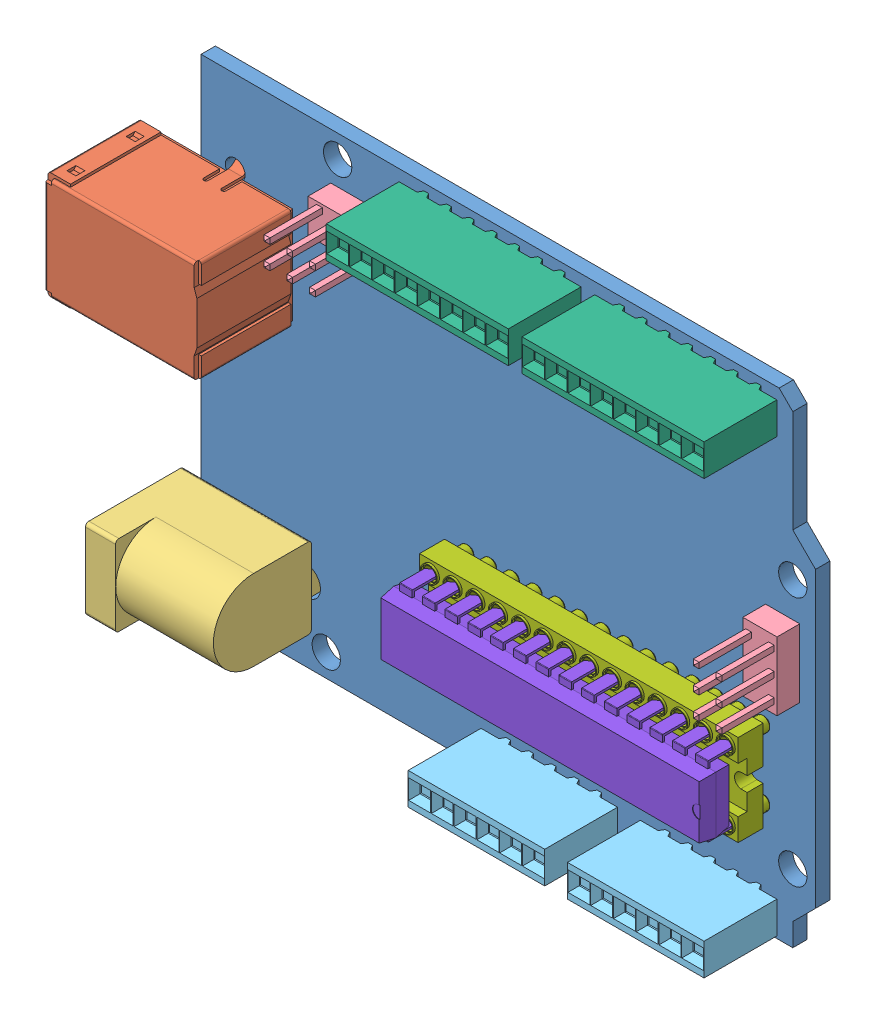
SolidWorks assembly uno-assy, configuration Default. Lengths in mm.
Overall size (75.05 53.34 15.91).
11 component instances, 8 part files, 29 mates.
Components (placement in the parent):
- uno-pcb-1: uno-pcb [Default] at origin size (68.58 53.34 1.6)
- SW3dPS-67068-0000-molex-1: SW3dPS-67068-0000-molex [Default] at (-40.7599 11.4299 0) x (0 -1 0) z (-1 0 0) size (14.9 15.43 17)
- RAPC732-1: RAPC732 [Default] at (-21.9709 -14.1224 0) x (0 -1 0) z (-1 0 0) size (11.28 14.91 15.39)
- 3x2-100-1: 3x2-100 [Default] at (-18.5421 20.828 0) size (7.62 3.81 11.94)
- 3x2-100-2: 3x2-100 [Default] at (29.3502 -1.32 0) x (0 1 0) z (0 0 1) size (7.62 3.81 11.94)
- C-0534237-04-3-1: C-0534237-04-3 [Default] at (22.8599 -24.13 8.636) x (-1 0 0) z (0 0 1) size (15.24 3.56 11.56)
- C-0534237-06-3-1: C-0534237-06-3 [Default] at (20.3199 24.13 8.636) x (-1 0 0) z (0 0 1) size (20.32 3.56 11.56)
- C-0534237-04-3-2: C-0534237-04-3 [Default] at (5.0799 -24.13 8.636) x (-1 0 0) z (0 0 1) size (15.24 3.56 11.56)
- C-0534237-06-3-2: C-0534237-06-3 [Default] at (-1.5241 24.13 8.636) x (-1 0 0) z (0 0 1) size (20.32 3.56 11.56)
- 28pdipskt-1: 28pdipskt [Default] at (24.7649 -10.287 1.4) x (0 -1 0) z (0 0 1) size (10.16 35.56 7.62)
- User Library-28 pin dip-1: User Library-28 pin dip [Default] at (6.9849 -10.287 6.873) x (0 1 0) z (1 0 0) size (7.87 6.22 35.94)
Mates (geometry in assembly coordinates):
- Coincident1: coincident aligned: axis of uno-pcb-1 through (-27.7699 12.6799 -1.6002) axis (0 0 1); axis of SW3dPS-67068-0000-molex-1 through (-27.7699 12.6799 -2.8) axis (0 0 1)
- Coincident2: coincident anti-aligned: plane of uno-pcb-1 through (-34.2899 26.67 0) normal (0 0 1); plane of SW3dPS-67068-0000-molex-1 through (-23.7599 17.4299 0) normal (0 0 -1)
- Parallel1: parallel aligned: plane of uno-pcb-1 through (-34.2899 -26.67 -1.6002) normal (-1 0 0); plane of SW3dPS-67068-0000-molex-1 through (-40.7599 17.4299 11) normal (-1 0 0)
- Concentric1: concentric aligned: circle of uno-pcb-1; circle of RAPC732-1
- Parallel2: parallel aligned: plane of uno-pcb-1 through (-34.2899 -26.67 -1.6002) normal (-1 0 0); plane of RAPC732-1 through (-36.2203 -14.5034 10.5918) normal (-1 0 0)
- Coincident5: coincident anti-aligned: plane of uno-pcb-1 through (-34.2899 26.67 0) normal (0 0 1); plane of RAPC732-1 through (-36.2203 -14.5034 0) normal (0 0 -1)
- Coincident6: coincident aligned: axis of uno-pcb-1 through (-18.5421 18.288 -1.6002) axis (0 0 1); axis of 3x2-100-1 through (-18.5421 18.288 -3.302) axis (0 0 1)
- Coincident7: coincident anti-aligned: plane of uno-pcb-1 through (-34.2899 26.67 0) normal (0 0 1); plane of 3x2-100-1 through (-18.5421 20.828 0) normal (0 0 -1)
- Coincident8: coincident aligned: axis of uno-pcb-1 through (31.8902 -1.32 -1.6002) axis (0 0 1); axis of 3x2-100-2 through (31.8902 -1.32 -3.302) axis (0 0 1)
- Coincident9: coincident anti-aligned: plane of uno-pcb-1 through (-34.2899 26.67 0) normal (0 0 1); plane of 3x2-100-2 through (29.3502 -1.32 0) normal (0 0 -1)
- Parallel3: parallel anti-aligned: plane of uno-pcb-1 through (34.2899 -21.59 -1.6002) normal (1 0 0); plane of 3x2-100-2 through (28.7152 -2.59 2.54) normal (-1 0 0)
- Parallel4: parallel aligned: plane of uno-pcb-1 through (-34.2899 26.67 -1.6002) normal (0 1 0); plane of 3x2-100-1 through (-19.8121 21.463 2.54) normal (0 1 0)
- Coincident12: coincident anti-aligned: axis of uno-pcb-1 through (29.2099 -24.13 -1.6002) axis (0 0 1); axis of C-0534237-04-3-1 through (29.2099 -24.13 -0.846) axis (0 0 -1)
- Parallel5: parallel aligned: plane of uno-pcb-1 through (-34.2899 -26.67 -1.6002) normal (0 -1 0); plane of C-0534237-04-3-1 through (30.4799 -25.908 8.636) normal (0 -1 0)
- Coincident15: coincident anti-aligned: axis of uno-pcb-1 through (11.4299 -24.13 -1.6002) axis (0 0 1); axis of C-0534237-04-3-2 through (11.4299 -24.13 -0.846) axis (0 0 -1)
- Coincident16: coincident anti-aligned: plane of uno-pcb-1 through (-34.2899 26.67 0) normal (0 0 1); plane of C-0534237-04-3-2 through (10.4139 -25.908 0) normal (0 0 -1)
- Coincident17: coincident anti-aligned: plane of uno-pcb-1 through (-34.2899 26.67 0) normal (0 0 1); plane of C-0534237-04-3-1 through (28.1939 -25.908 0) normal (0 0 -1)
- Coincident18: coincident anti-aligned: axis of uno-pcb-1 through (29.2099 24.13 -1.6002) axis (0 0 1); axis of C-0534237-06-3-1 through (29.2099 24.13 -1.201) axis (0 0 -1)
- Coincident19: coincident anti-aligned: plane of uno-pcb-1 through (-34.2899 26.67 0) normal (0 0 1); plane of C-0534237-06-3-1 through (28.1939 25.908 0) normal (0 0 -1)
- Parallel6: parallel aligned: plane of uno-pcb-1 through (-34.2899 26.67 -1.6002) normal (0 1 0); plane of C-0534237-06-3-1 through (10.1599 25.908 8.636) normal (0 1 0)
- Coincident21: coincident anti-aligned: axis of uno-pcb-1 through (7.3659 24.13 -1.6002) axis (0 0 1); axis of C-0534237-06-3-2 through (7.3659 24.13 -1.201) axis (0 0 -1)
- Coincident22: coincident anti-aligned: plane of uno-pcb-1 through (-34.2899 26.67 0) normal (0 0 1); plane of C-0534237-06-3-2 through (6.3499 25.908 0) normal (0 0 -1)
- Parallel7: parallel aligned: plane of uno-pcb-1 through (-34.2899 26.67 -1.6002) normal (0 1 0); plane of C-0534237-06-3-2 through (-11.6841 25.908 8.636) normal (0 1 0)
- Coincident25: coincident aligned: axis of uno-pcb-1 through (28.5749 -6.477 -1.6002) axis (0 0 1); axis of 28pdipskt-1 through (28.5749 -6.477 -3.18) axis (0 0 1)
- Parallel8: parallel aligned: plane of uno-pcb-1 through (-34.2899 -26.67 -1.6002) normal (0 -1 0); plane of 28pdipskt-1 through (-5.7151 -15.367 4.19) normal (0 -1 0)
- Coincident27: coincident anti-aligned: plane of uno-pcb-1 through (-34.2899 26.67 0) normal (0 0 1); plane of 28pdipskt-1 through (28.5749 -14.097 0) normal (0 0 -1)
- Coincident28: coincident aligned: axis of 28pdipskt-1 through (28.5749 -6.477 4.19) axis (0 0 -1); axis of User Library-28 pin dip-1 through (28.5749 -6.477 2.508) axis (0 0 -1)
- Parallel9: parallel aligned: line of uno-pcb-1 through (-34.2899 -26.67 0) axis (1 0 0); line of User Library-28 pin dip-1 through (-5.7028 -13.2593 8.524) axis (1 0 0)
- Distance1: distance = 2.032 mm anti-aligned: plane of 28pdipskt-1 through (-5.7151 -7.707 3.19) normal (0 0 1); plane of User Library-28 pin dip-1 through (19.8754 -13.462 5.222) normal (0 0 -1)
